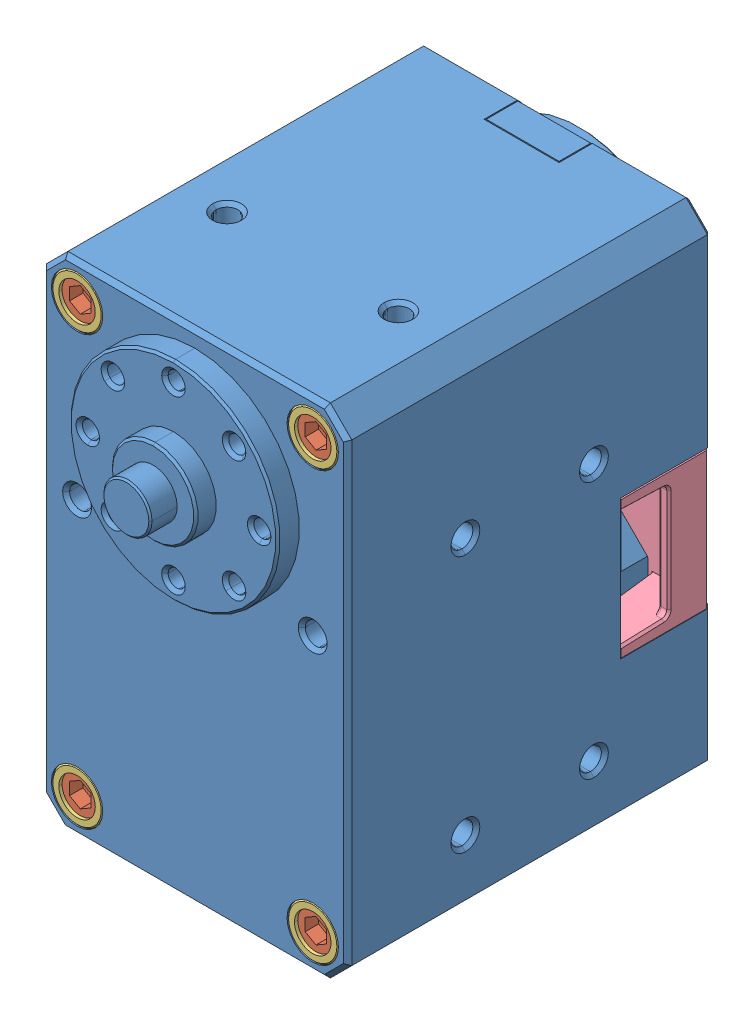
SolidWorks assembly XH-430_W-210, configuration Default. Lengths in mm.
Overall size (28.5 46.5 42.4).
19 component instances, 4 part files, 0 mates.
Components (placement in the parent):
- XM,H-430_idler.stp-1: XM,H-430_idler.stp [Default] at origin size (28.5 46.5 42.4)
  - DUMMY_DC12.stp-1: DUMMY_DC12.stp [Default] at origin size (28.5 46.5 42.4)
  - WBH_M2_5X12.stp-1: WBH_M2_5X12.stp [Default] at (-11 8 14.2) size (4.5 4.5 14.5)
  - WBH_M2_5X12.stp-2: WBH_M2_5X12.stp [Default] at (11 8 14.2) size (4.5 4.5 14.5)
  - WBH_M2_5X12.stp-3: WBH_M2_5X12.stp [Default] at (-11 -32 14.2) size (4.5 4.5 14.5)
  - WBH_M2_5X12.stp-4: WBH_M2_5X12.stp [Default] at (11 -32 14.2) size (4.5 4.5 14.5)
  - WBH_M2_5X12.stp-5: WBH_M2_5X12.stp [Default] at (11 -32 -14.2) x (-1 0 0) z (0 0 -1) size (4.5 4.5 14.5)
  - WBH_M2_5X12.stp-6: WBH_M2_5X12.stp [Default] at (-11 -32 -14.2) x (-1 0 0) z (0 0 -1) size (4.5 4.5 14.5)
  - WBH_M2_5X12.stp-7: WBH_M2_5X12.stp [Default] at (11 8 -14.2) x (-1 0 0) z (0 0 -1) size (4.5 4.5 14.5)
  - WBH_M2_5X12.stp-8: WBH_M2_5X12.stp [Default] at (-11 8 -14.2) x (-1 0 0) z (0 0 -1) size (4.5 4.5 14.5)
  - DC12_A01_SPACER_RING_1.stp-1: DC12_A01_SPACER_RING_1.stp [Default] at (11 8 -14.2) x (1 0 0) z (0 1 0) size (4.8 2.8 4.8)
  - DC12_A01_SPACER_RING_1.stp-2: DC12_A01_SPACER_RING_1.stp [Default] at (-11 8 -14.2) x (1 0 0) z (0 1 0) size (4.8 2.8 4.8)
  - DC12_A01_SPACER_RING_1.stp-3: DC12_A01_SPACER_RING_1.stp [Default] at (11 -32 -14.2) x (1 0 0) z (0 1 0) size (4.8 2.8 4.8)
  - DC12_A01_SPACER_RING_1.stp-4: DC12_A01_SPACER_RING_1.stp [Default] at (-11 -32 -14.2) x (1 0 0) z (0 1 0) size (4.8 2.8 4.8)
  - DC12_A01_SPACER_RING_1.stp-5: DC12_A01_SPACER_RING_1.stp [Default] at (-11 -32 14.2) x (-1 0 0) z (0 1 0) size (4.8 2.8 4.8)
  - DC12_A01_SPACER_RING_1.stp-6: DC12_A01_SPACER_RING_1.stp [Default] at (11 -32 14.2) x (-1 0 0) z (0 1 0) size (4.8 2.8 4.8)
  - DC12_A01_SPACER_RING_1.stp-7: DC12_A01_SPACER_RING_1.stp [Default] at (-11 8 14.2) x (-1 0 0) z (0 1 0) size (4.8 2.8 4.8)
  - DC12_A01_SPACER_RING_1.stp-8: DC12_A01_SPACER_RING_1.stp [Default] at (11 8 14.2) x (-1 0 0) z (0 1 0) size (4.8 2.8 4.8)
  - DC12_A01_CVR_CABLE_5.stp-1: DC12_A01_CVR_CABLE_5.stp [Default] at (0 -0.05 0) size (28.5 13.4 8.8)
